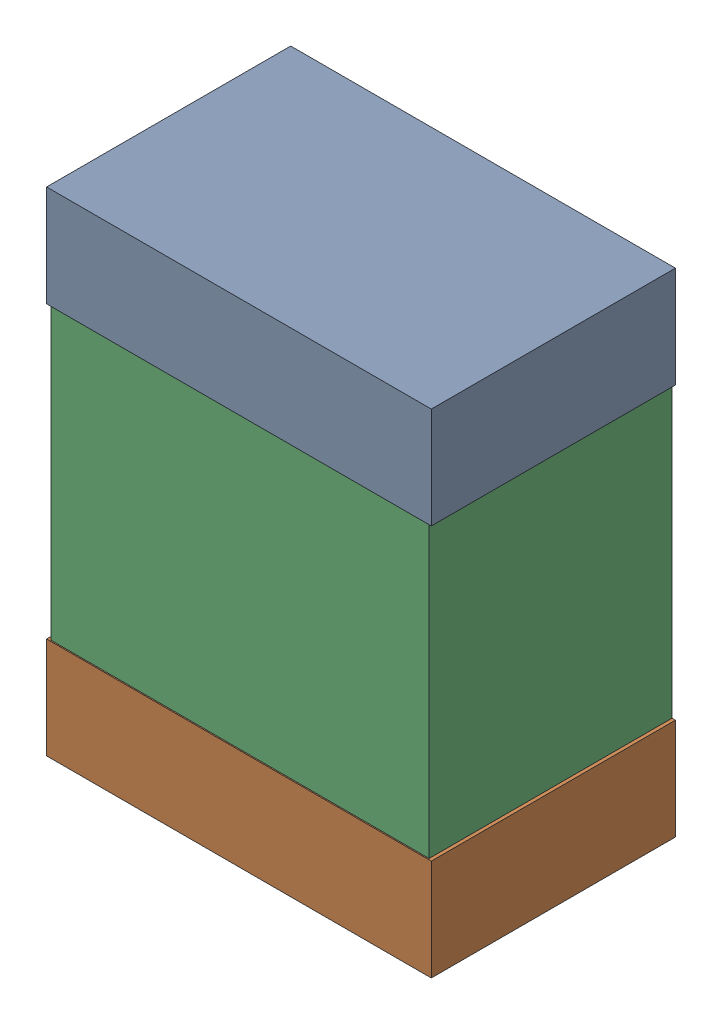
SolidWorks assembly CoutSlByp1Kanaloa_v2.0.0_Power, configuration Default. Lengths in mm.
Overall size (2.85 3.65 1.81).
6 component instances, 2 part files, 0 mates.
Components (placement in the parent):
- 334789552-1: 334789552 [Default] at (89.8 53.2 0) size (2.85 0.75 1.81)
  - Extruded_9-1: Extruded_9 [Default] at origin size (2.85 0.75 1.81)
- 334789552-2: 334789552 [Default] at (89.8 50.3 0) size (2.85 0.75 1.81)
  - Extruded_9-1: Extruded_9 [Default] at origin size (2.85 0.75 1.81)
- 334789424-1: 334789424 [Default] at (89.8 51.75 0) size (2.8 3.6 1.8)
  - Extruded_10-1: Extruded_10 [Default] at origin size (2.8 3.6 1.8)
